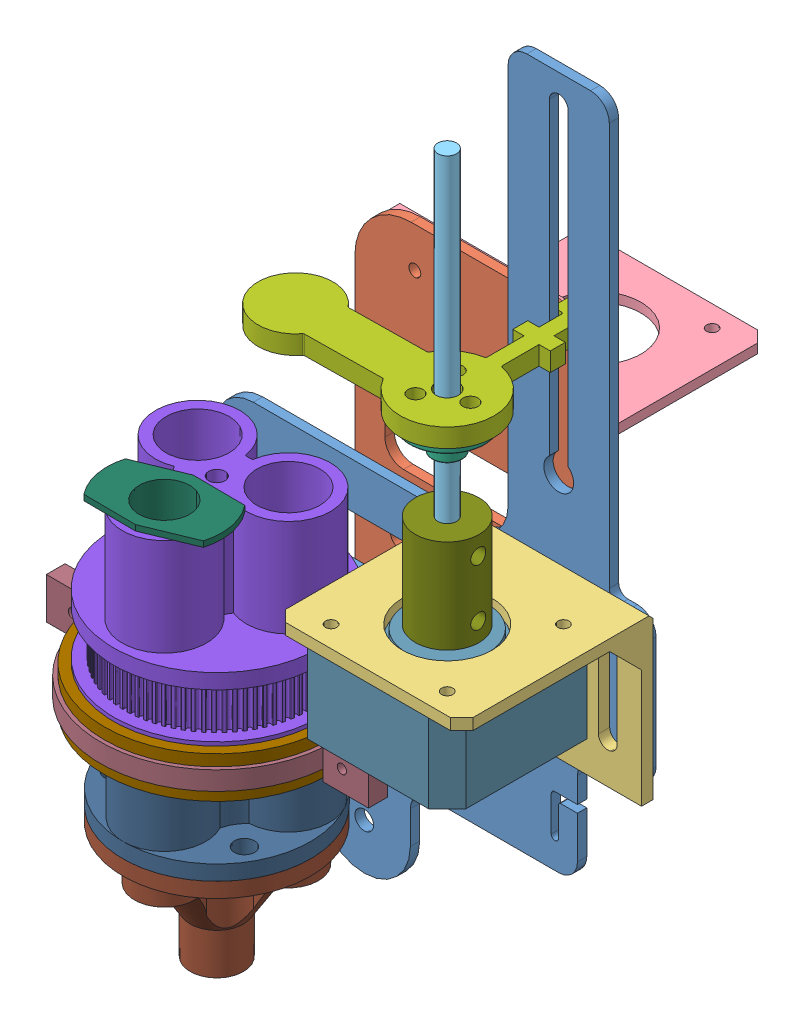
SolidWorks assembly extrusion system assembly, configuration Default. Lengths in mm.
Overall size (120 211.6 156.48).
17 component instances, 16 part files, 34 mates.
Components (placement in the parent):
- Aluminium plate 1-1: Aluminium plate 1 [Default] at origin size (115 211.05 2.5)
- Aluminium plate 2-1: Aluminium plate 2 [Default] at (-24.8 0 -29.5) size (64 125.41 2.5)
- nema_17_holder-1: nema_17_holder [Default] at (39.6 57.4093 32.35) x (1 0 0) z (0 -1 0) size (50 51 43)
- NEMA 17 HOLDER 2-1: NEMA 17 HOLDER 2 [Default] at (-12.4 51.5 -59.35) x (1 0 0) z (0 1 0) size (50 51 32.5)
- lead screw-1: lead screw [Default] at (39.6 119.9093 32.35) x (0 1 0) z (0 0 1) size (95 5 5)
- trap nut-1: trap nut [Default] at (39.6 103.8187 32.35) x (-0.5 0 0.866025) z (0 1 0) size (20 20 9.4)
- pusher-1: pusher [Default] at (39.6 106.8187 32.35) size (62.5 5 50.5)
- syringe barrel assembly-1: syringe barrel assembly [Default] at (-12.4 27.4093 41.8428) size (68.27 112.01 68.27)
  - barrel mid 1-1: barrel mid 1 [Default] at origin size (55 48.5 55)
  - stainless steel ring-1: stainless steel ring [Default] at (0 -5.5 0) size (60 11 60)
  - barrel bottom 1-1: barrel bottom 1 [Default] at (0 -33 0) x (0.999998 0 -0.001745) z (0.001745 0 0.999998) size (55 27.4 55)
  - mixing chamber 1-1: mixing chamber 1 [Default] at (0 -68 0) x (-0.866897 0 -0.498488) z (0 1 0) size (50 50 36.01)
- barrel lock p1-1: barrel lock p1 [Default] at (-12.4 19.4093 41.8428) x (0 0 -1) z (1 0 0) size (42.84 22 80)
- barrel lock p2-1: barrel lock p2 [Default] at (-12.4 24.4093 41.8428) x (0 0 -1) z (-1 0 0) size (33.5 11 86)
- Nema17 motor-1: Nema17 motor [Default] at (39.6 33.4093 32.35) size (42.3 38 42.3)
- syringe 10 ml part1-1: syringe 10 ml part1 [Default] at (-12.4 32.9093 55.8428) x (0 -1 0) z (0.190524 0 0.981683) size (86.5 30.6 19.5)
- coupler-1: coupler [Default] at (39.6 57.4093 32.35) size (17 25 17)
Mates (geometry in assembly coordinates):
- Concentric5: concentric: cylinder of nema_17_holder-1 through (39.6 54.4093 32.35) axis (0 1 0) radius 12; cylinder of lead screw-1 through (39.6 110.7738 32.35) axis (0 -1 0) radius 2.5
- Distance12: distance = 15 mm: plane of lead screw-1 through (37.1 72.4093 32.35) normal (0 -1 0); plane of nema_17_holder-1 through (39.6 57.4093 32.35) normal (0 1 0)
- Concentric6: concentric: cylinder of lead screw-1 through (39.6 110.7738 32.35) axis (0 -1 0) radius 2.5; cylinder of trap nut-1 through (39.6 106.8187 32.35) axis (0 -1 0) radius 2.5
- Distance13: distance = 5 mm: plane of trap nut-1 through (39.6 93.2281 32.35) normal (0 -1 0); plane of lead screw-1 through (37.1 72.4093 32.35) normal (0 -1 0)
- Concentric7: concentric: cylinder of lead screw-1 through (39.6 110.7738 32.35) axis (0 -1 0) radius 2.5; cylinder of pusher-1 through (39.6 111.8187 32.35) axis (0 -1 0) radius 3
- Coincident19: coincident: plane of trap nut-1 through (39.6 106.8187 32.35) normal (0 1 0); plane of pusher-1 through (39.6 106.8187 32.35) normal (0 -1 0)
- Concentric8: concentric: cylinder of trap nut-1 through (45.8 106.8187 32.35) axis (0 -1 0) radius 1.5; cylinder of pusher-1 through (45.8 111.8187 32.35) axis (0 -1 0) radius 2
- Coincident20: coincident: plane of Aluminium plate 2-1 through (-24.8 0 -29.5) normal (0 1 0); plane of assembly through (0 0 0) normal (0 1 0)
- Distance14: distance = 27 mm: plane of Aluminium plate 2-1 through (-24.8 0 -27) normal (0 0 1); plane of Aluminium plate 1-1 through (0 0 0) normal (0 0 -1)
- Distance15: distance = 0.5 mm: plane of Aluminium plate 1-1 through (18.6 40.9093 -0.001) normal (0 -1 0); plane of syringe barrel assembly-1/barrel mid 1-1 through (-12.4 40.4093 41.8428) normal (0 -1 0)
- Coincident23: coincident: plane of barrel lock p1-1 through (-12.4 24.4093 2.5) normal (0 0 -1); plane of Aluminium plate 1-1 through (0 0 2.5) normal (0 0 1)
- Distance16: distance = 12.4 mm: plane of barrel lock p1-1 through (-12.4 19.4093 41.8428) normal (1 0 0); plane of assembly through (0 0 0) normal (1 0 0)
- Concentric9: concentric: cylinder of syringe barrel assembly-1/stainless steel ring-1 through (-12.4 41.8967 41.8428) axis (0 1 0) radius 25; cylinder of barrel lock p1-1 through (-12.4 24.4093 41.8428) axis (0 -1 0) radius 25
- Coincident26: coincident: plane of syringe barrel assembly-1/stainless steel ring-1 through (-37.4 24.4093 41.8428) normal (0 -1 0); plane of barrel lock p1-1 through (-12.4 24.4093 41.8428) normal (0 1 0)
- Concentric10: concentric: cylinder of Aluminium plate 1-1 through (-12.4 -28.75 -7.5) axis (0 0 1) radius 2.5; cylinder of Aluminium plate 2-1 through (-12.4 -28.75 -19.5) axis (0 0 -1) radius 2.5
- Coincident27: coincident: plane of syringe barrel assembly-1/stainless steel ring-1 through (-37.4 24.4093 41.8428) normal (0 -1 0); plane of barrel lock p2-1 through (-12.4 24.4093 41.8428) normal (0 1 0)
- Concentric11: concentric: cylinder of syringe barrel assembly-1/stainless steel ring-1 through (-12.4 41.8967 41.8428) axis (0 1 0) radius 25; cylinder of barrel lock p2-1 through (-12.4 19.4093 41.8428) axis (0 1 0) radius 25
- Coincident28: coincident: plane of barrel lock p1-1 through (-12.4 24.4093 41.8428) normal (0 0 1); plane of barrel lock p2-1 through (-12.4 19.4093 41.8428) normal (0 0 -1)
- Distance17: distance = 27 mm: plane of nema_17_holder-1 through (14.6 54.4093 50.5) normal (-1 0 0); plane of syringe barrel assembly-1/barrel mid 1-1 through (-12.4 27.4093 41.8428) normal (1 0 0)
- Distance18: distance = 82 mm: plane of pusher-1 through (39.6 102.6281 32.35) normal (0 -1 0); plane of syringe barrel assembly-1/barrel mid 1-1 through (-12.4 70.4093 41.8428) normal (0 1 0)
- Distance19: distance = 13 mm: plane of nema_17_holder-1 through (39.6 57.4093 32.35) normal (0 1 0); plane of syringe barrel assembly-1/barrel mid 1-1 through (-12.4 44.4093 41.8428) normal (0 1 0)
- Coincident35: coincident: plane of Aluminium plate 2-1 through (-24.8 0 -29.5) normal (0 0 -1); plane of NEMA 17 HOLDER 2-1 through (12.6 54 -29.5) normal (0 0 1)
- Distance21: distance = 7 mm: plane of NEMA 17 HOLDER 2-1 through (-37.4 54 -59.35) normal (-1 0 0); plane of Aluminium plate 2-1 through (-44.4 0 -29.501) normal (-1 0 0)
- Distance22: distance = 10.5 mm: plane of Aluminium plate 2-1 through (-24.8 41 -29.501) normal (0 -1 0); plane of NEMA 17 HOLDER 2-1 through (-12.4 51.5 -59.35) normal (0 -1 0)
- Parallel1: parallel: plane of syringe barrel assembly-1/barrel mid 1-1 through (-12.4 27.4093 41.8428) normal (1 0 0); plane of assembly through (0 0 0) normal (1 0 0)
- Concentric12: concentric: cylinder of nema_17_holder-1 through (39.6 54.4093 32.35) axis (0 1 0) radius 12; cylinder of Nema17 motor-1 through (39.6 56.4093 32.35) axis (0 -1 0) radius 11
- Concentric13: concentric: cylinder of Nema17 motor-1 through (55.1 51.4093 16.85) axis (0 1 0) radius 1.5; cylinder of nema_17_holder-1 through (55.1 54.4093 16.85) axis (0 1 0) radius 1.5
- Coincident36: coincident: plane of nema_17_holder-1 through (39.6 54.4093 32.35) normal (0 -1 0); plane of Nema17 motor-1 through (39.6 54.4093 32.35) normal (0 1 0)
- Coincident37: coincident: plane of Aluminium plate 1-1 through (0 0 2.5) normal (0 0 1); plane of nema_17_holder-1 through (64.6 54.4093 2.5) normal (0 0 -1)
- Concentric14: concentric: cylinder of syringe barrel assembly-1/barrel mid 1-1 through (-12.4 70.4093 55.8428) axis (0 -1 0) radius 8.425; cylinder of syringe 10 ml part1-1 through (-12.4 83.0267 55.8428) axis (0 1 0) radius 8.25
- Coincident38: coincident: plane of syringe barrel assembly-1/barrel mid 1-1 through (-12.4 70.4093 41.8428) normal (0 1 0); plane of syringe 10 ml part1-1 through (-4.3011 70.4093 54.271) normal (0 -1 0)
- Concentric15: concentric: cylinder of Nema17 motor-1 through (39.6 71.4093 32.35) axis (0 -1 0) radius 2.5; cylinder of coupler-1 through (39.6 82.4093 32.35) axis (0 -1 0) radius 2.5
- Distance23: distance = 1 mm: plane of coupler-1 through (39.6 57.4093 32.35) normal (0 -1 0); plane of Nema17 motor-1 through (39.6 56.4093 32.35) normal (0 1 0)
- Parallel2: parallel: plane of Aluminium plate 1-1 through (42 0 -7.5) normal (-1 0 0); plane of pusher-1 through (41.6 111.8187 32.35) normal (1 0 0)
